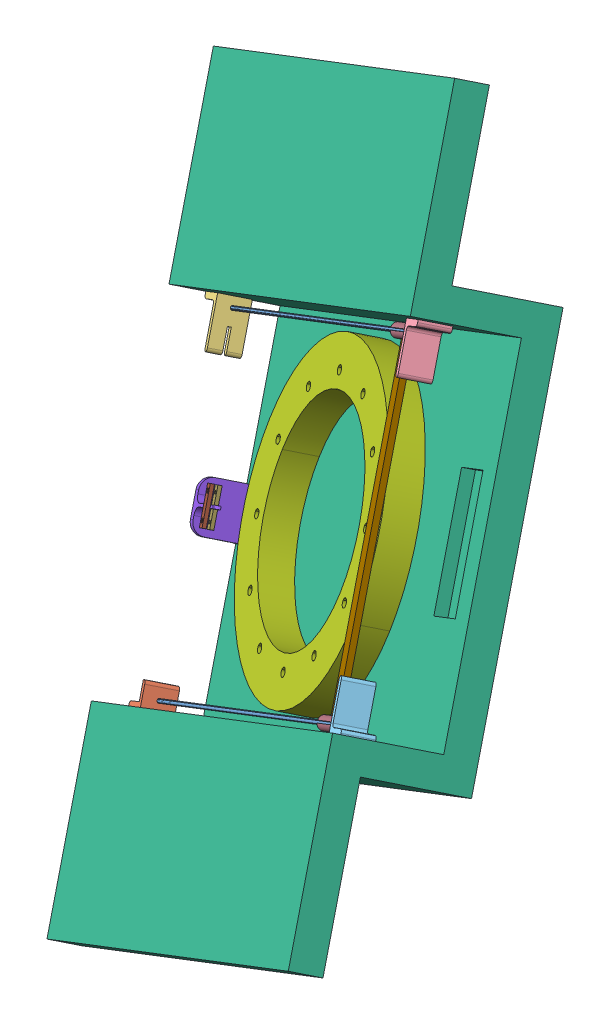
SolidWorks assembly couverture_anneau, configuration Default. Lengths in mm.
Overall size (587.99 736.87 546.03).
16 component instances, 13 part files, 0 mates.
Components (placement in the parent):
- couverture_anneau.STEP-1: couverture_anneau.STEP [Default] at origin size (587.99 736.87 546.03)
  - tige.STEP-1: tige.STEP [Default] at (92.3943 116.8748 -274.4975) x (-0.456696 0.865255 -0.206792) z (0.37015 -0.026558 -0.928592) size (3.18 356 3.17)
  - tige.STEP-2: tige.STEP [Default] at (154.4063 -55.1619 -157.7952) x (-0.58786 0.687392 0.426513) z (-0.001708 0.526178 -0.850373) size (3.18 356 3.17)
  - braquette3.STEP-1: braquette3.STEP [Default] at (0.6109 -142.9251 -150.3977) x (-0.283104 0.791161 -0.54214) z (0.515203 -0.351333 -0.781749) size (20 22 25)
  - braquette4.STEP-1: braquette4.STEP [Default] at (-67.3341 46.9536 -280.5113) x (-0.283104 0.791161 -0.54214) z (0.515203 -0.351333 -0.781749) size (39.83 22 25)
  - braquette5.STEP-1: braquette5.STEP [Default] at (211.0117 235.9632 -150.0354) x (-0.283104 0.791161 -0.54214) z (-0.515203 0.351333 0.781749) size (39.83 51.31 25)
  - braquette6.STEP-1: braquette6.STEP [Default] at (280.5127 68.9476 -61.1512) x (0.283104 -0.791161 0.54214) z (0.515203 -0.351333 -0.781749) size (39.83 52 25)
  - Plancher.STEP-1: Plancher.STEP [Default] at (380.5379 -77.2334 134.4251) x (-0.283104 0.791161 -0.54214) z (-0.808961 -0.500629 -0.308145) size (600 105 450)
  - anneau_rover.STEP-1: anneau_rover.STEP [Default] at (120.0458 46.252 -195.0808) x (0.159305 0.93548 -0.315435) z (0.842133 0.037976 0.537931) size (255.02 26.67 255.02)
  - basesnapfit.STEP-1: basesnapfit.STEP [Default] at (-31.0478 -36.113 -257.641) x (0.283104 -0.791161 0.54214) z (-0.808961 -0.500629 -0.308145) size (40 42 55)
  - tigecouv.STEP-1: tigecouv.STEP [Default] at (254.0241 36.9822 -45.0866) x (0.808961 0.500629 0.308145) z (-0.515203 0.351333 0.781749) size (10 253 5)
  - interfacema01.STEP-1: interfacema01.STEP [Default] at (1.7119 -41.5536 -233.6059) x (-0.283104 0.791161 -0.54214) z (-0.515203 0.351333 0.781749) size (30 10 5)
  - interfacema02.STEP-1: interfacema02.STEP [Default] at (-20.5713 -28.537 -202.974) x (-0.283104 0.791161 -0.54214) z (0.808961 0.500629 0.308145) size (30 3 5)
  - interfacema03.STEP-1: interfacema03.STEP [Default] at (-17.7377 -30.4693 -207.2736) x (-0.283104 0.791161 -0.54214) z (0.808961 0.500629 0.308145) size (30 3 5)
  - wagon2 - Copy.STEP-1: wagon2 - Copy.STEP [Default] at (240.3514 30.5481 -47.3362) x (0.283104 -0.791161 0.54214) z (0.808961 0.500629 0.308145) size (18 11 40)
  - wagon2 - Copy.STEP-2: wagon2 - Copy.STEP [Default] at (201.044 250.712 -172.1873) x (-0.283104 0.791161 -0.54214) z (-0.808961 -0.500629 -0.308145) size (18 11 40)
